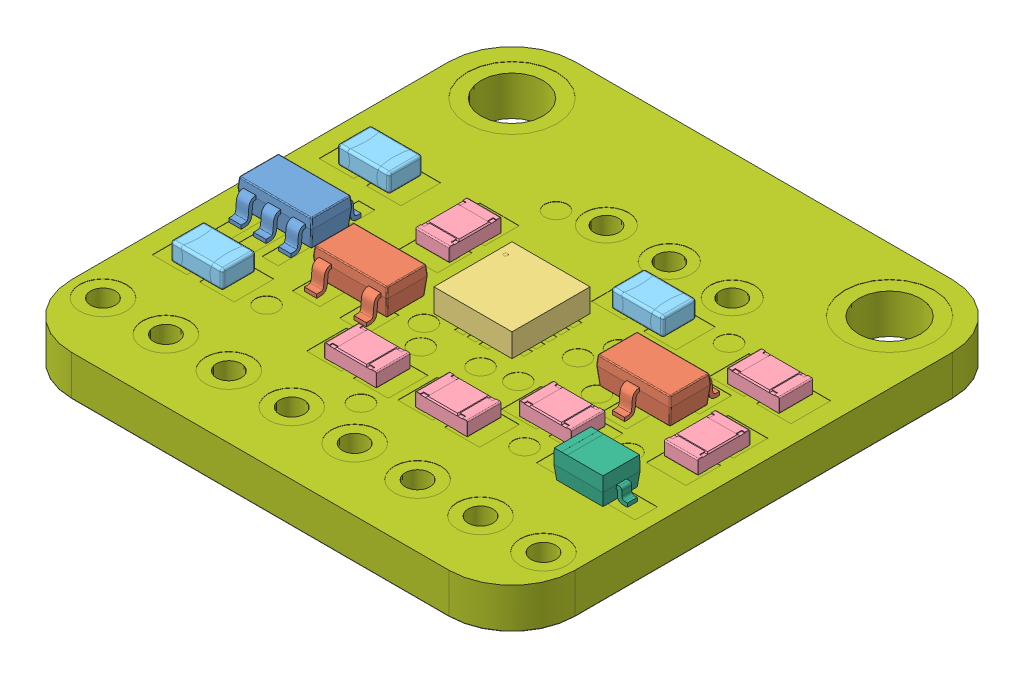
SolidWorks assembly LIS3DH v9, configuration Default. Lengths in mm.
Overall size (20.32 2.79 20.32).
17 component instances, 8 part files, 0 mates.
Components (placement in the parent):
- LIS3DH v9.step-1: LIS3DH v9.step [Default] at origin size (20.32 2.79 20.32)
  - SOT23-5.step-1: SOT23-5.step [Default] at (2.413 1.575 -9.144) x (0 0 1) z (0 1 0) size (2.84 3.03 1.19)
  - SOT23-3.step-1: SOT23-3.step [Default] at (6.35 1.575 -8.255) x (0 0 1) z (0 1 0) size (2.84 3.03 1.19)
  - SOT23-3.step-2: SOT23-3.step [Default] at (15.875 1.575 -10.16) x (0 0 -1) z (0 1 0) size (2.84 3.03 1.19)
  - 16-LGA-3X3.step-1: 16-LGA-3X3.step [Default] at (8.585 1.68 -11.735) size (3.15 0.99 3.15)
  - SMD Resistor 0805.step-1: SMD Resistor 0805.step [Default] at (6.35 1.57 -11.811) x (0 0 1) z (0 1 0) size (2.1 1.35 0.6)
  - SMD Resistor 0805.step-2: SMD Resistor 0805.step [Default] at (18.796 1.57 -9.398) x (0 0 -1) z (0 1 0) size (2.1 1.35 0.6)
  - SMD Resistor 0805.step-3: SMD Resistor 0805.step [Default] at (8.89 1.57 -5.588) x (1 0 0) z (0 1 0) size (2.1 1.35 0.6)
  - SMD Resistor 0805.step-4: SMD Resistor 0805.step [Default] at (12.4335 1.57 -5.715) x (1 0 0) z (0 1 0) size (2.1 1.35 0.6)
  - SMD Resistor 0805.step-5: SMD Resistor 0805.step [Default] at (14.8465 1.57 -7.493) x (1 0 0) z (0 1 0) size (2.1 1.35 0.6)
  - SMD Resistor 0805.step-6: SMD Resistor 0805.step [Default] at (17.907 1.57 -12.827) x (1 0 0) z (0 1 0) size (2.1 1.35 0.6)
  - Cap 0805.step-1: Cap 0805.step [Default] at (12.954 1.6 -13.081) x (1 0 0) z (0 1 0) size (2.1 1.35 0.75)
  - Cap 0805.step-2: Cap 0805.step [Default] at (2.413 2.35 -5.842) x (1 0 0) z (0 -1 0) size (2.1 1.35 0.75)
  - Cap 0805.step-3: Cap 0805.step [Default] at (2.413 2.35 -12.573) x (1 0 0) z (0 -1 0) size (2.1 1.35 0.75)
  - SOD-323.step-1: SOD-323.step [Default] at (16.805 2.205 -5.769) x (-1 0 0) z (0 0 -1) size (2.86 1.14 1.5)
  - LIS3DH.step-1: LIS3DH.step [Default] at origin size (20.32 1.6 20.32)
  - LIS3DH-0.step-1: LIS3DH-0.step [Default] at origin size (20.32 0.01 20.32)
